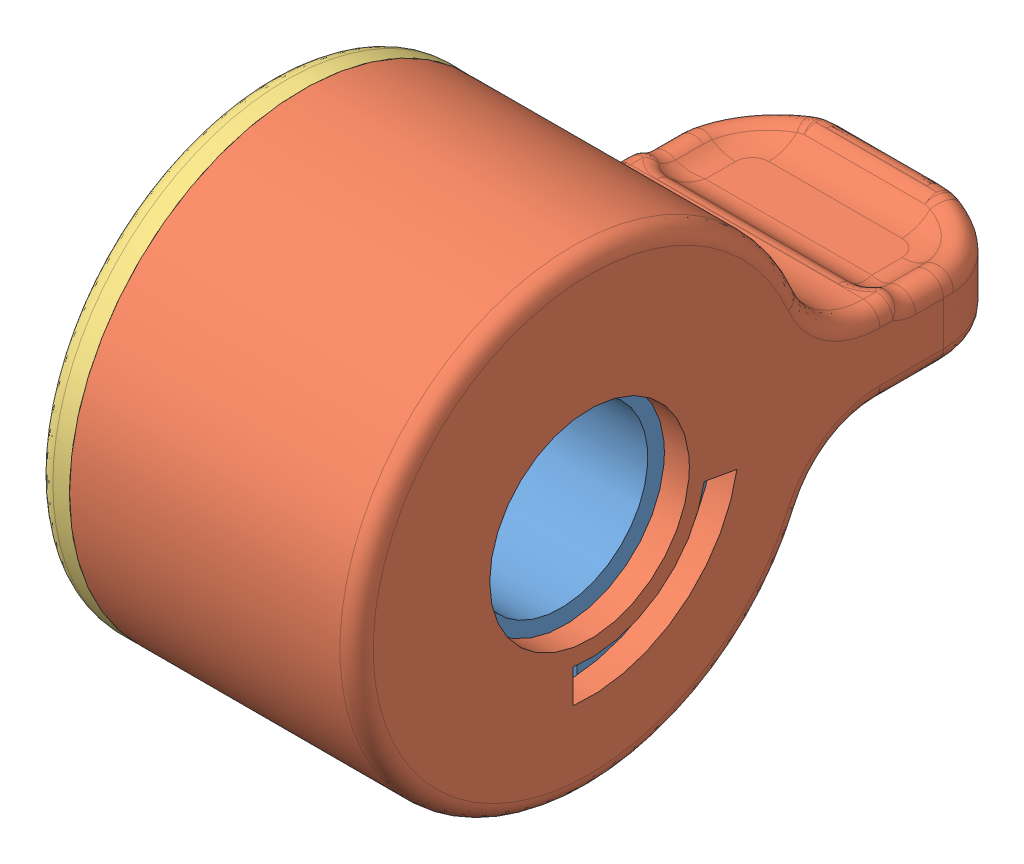
SolidWorks assembly acelerador_patinete, configuration Predeterminado. Lengths in mm.
Overall size (38.51 56 80.55).
3 component instances, 3 part files, 4 mates.
Components (placement in the parent):
- Pieza1^acelerador_patinete-1: Pieza1^acelerador_patinete [Predeterminado] at origin size (27 46 46) (virtual)
- Pieza2^acelerador_patinete-1: Pieza2^acelerador_patinete [Predeterminado] at origin size (34.51 56 80.55) (virtual)
- Pieza3^acelerador_patinete-1: Pieza3^acelerador_patinete [Predeterminado] at (-4 0 0) x (0 0 1) z (-1 0 0) size (56 56 7) (virtual)
Mates (geometry in assembly coordinates):
- EnPosición1: in place: plane of ? through (-3.5 0 0) normal (-1 0 0); plane of ? through (-3.5 0 0) normal (-1 0 0); moOrthogonalPlaneRef_w of ? through (-3.5 0 0) normal (-1 0 0); line of ? through (-55 -3.5 0) axis (0 0 1); plane of ? through (-3.5 0 0) normal (-1 0 0); plane of ? through (-3.5 0 0) normal (0 0 1); plane of ? through (-4 0 0) normal (-1 0 0); unknown of Pieza3^acelerador_patinete-1
- Coincidente1: coincident aligned: plane of Pieza2^acelerador_patinete-1; plane of Pieza3^acelerador_patinete-1
- Coincidente2: coincident aligned: moOrthogonalPlaneRef_w of Pieza2^acelerador_patinete-1 through (-4 0 0) normal (0 1 0); plane of Pieza3^acelerador_patinete-1
- Coincidente3: coincident anti-aligned: moOrthogonalPlaneRef_w of Pieza2^acelerador_patinete-1 through (-4 0 0) normal (0 0 -1); plane of Pieza3^acelerador_patinete-1 through (-4 0 0) normal (0 0 1)
